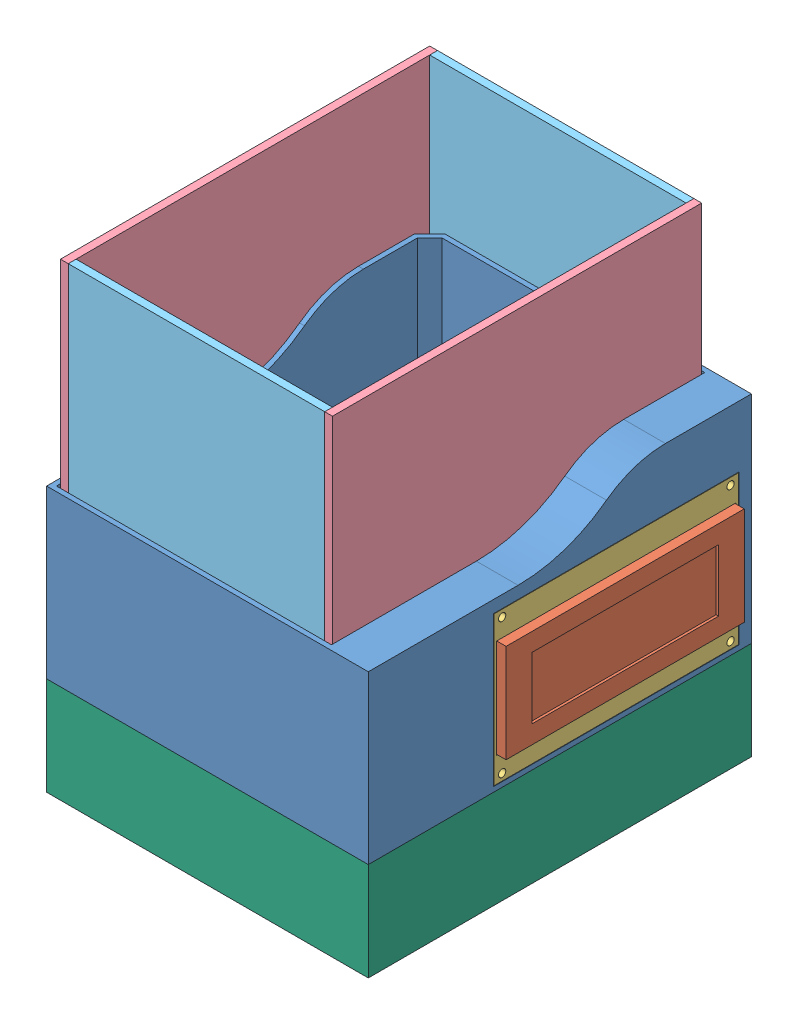
SolidWorks assembly MontagemGeral, configuration Valor predeterminado. Lengths in mm.
Overall size (134.6 188 156).
8 component instances, 6 part files, 22 mates.
Components (placement in the parent):
- Base-1: Base [Valor predeterminado] at origin size (131 88 156)
- 2004A-1: 2004A [Predeterminado] at (66.3 24.5 -23) x (0 0 -1) z (1 0 0) size (98 60 11.1)
- EspelhoFrontalLCD-1: EspelhoFrontalLCD [Valor predeterminado] at (68 0 0) x (0 0 -1) z (1 0 0) size (99.6 60.6 5)
- Acrilico Lateral-1: Acrilico Lateral [Valor predeterminado] at (55.5875 95 0) x (0 0 1) z (-1 0 0) size (150.35 90 3.17)
- Acrilico Lateral-2: Acrilico Lateral [Valor predeterminado] at (-52 95 0) x (0 0 1) z (-1 0 0) size (150.35 90 3.17)
- AcrilicoFrontal-1: AcrilicoFrontal [Valor predeterminado] at (0.2062 95 72) size (104.41 90 3.17)
- AcrilicoFrontal-2: AcrilicoFrontal [Valor predeterminado] at (0.2062 95 -75.175) size (104.41 90 3.17)
- CasePlacas-1: CasePlacas [Valor predeterminado] at (7.5 -48 0) size (131 40 156)
Mates (geometry in assembly coordinates):
- Coincidente1: coordinate: point of Base-1
- Simétrico1: symmetric aligned: plane of Base-1 through (53 55 -73) normal (0 0 1); plane of 2004A-1 through (53 55 27) normal (0 0 -1); plane of Base-1 through (66.3 24.5 -23) normal (0 0 -1)
- Simétrico2: symmetric aligned: plane of Base-1 through (53 -6 27) normal (0 1 0); plane of 2004A-1 through (53 55 27) normal (0 -1 0); plane of Base-1 through (66.3 24.5 -23) normal (0 1 0)
- Concêntrico1: concentric anti-aligned: cylinder of 2004A-1 through (65.5 -3 23.5) axis (1 0 0) radius 1.5; cylinder of EspelhoFrontalLCD-1 through (73 -3 23.5) axis (-1 0 0) radius 1.5
- Concêntrico2: concentric anti-aligned: cylinder of 2004A-1 through (65.5 52 -69.5) axis (1 0 0) radius 1.5; cylinder of EspelhoFrontalLCD-1 through (73 52 -69.5) axis (-1 0 0) radius 1.5
- Distância3: distance = 12.5 mm anti-aligned: plane of 2004A-1 through (65.5 24.5 -23) normal (-1 0 0); plane of Base-1 through (53 0 0) normal (1 0 0)
- Coincidente3: coincident aligned: plane of Base-1 through (73 40 -43) normal (1 0 0); plane of EspelhoFrontalLCD-1 through (73 0 0) normal (1 0 0)
- Largura1: width anti-aligned: plane of Base-1 through (56 50 -43) normal (-1 0 0); plane of Acrilico Lateral-1 through (52 50 -65.8284) normal (1 0 0); plane of Base-1 through (55.5875 95 0) normal (1 0 0); plane of Acrilico Lateral-1 through (52.4125 95 0) normal (-1 0 0)
- Largura2: width anti-aligned: plane of Base-1 through (56 50 -76) normal (0 0 1); plane of Acrilico Lateral-1 through (-56 50 76) normal (0 0 -1); plane of Base-1 through (52.4125 50 -75.175) normal (0 0 -1); plane of Acrilico Lateral-1 through (52.4125 50 75.175) normal (0 0 1)
- Coincidente4: coincident anti-aligned: plane of Base-1 through (0 50 0) normal (0 1 0); plane of Acrilico Lateral-1 through (52.4125 50 -75.175) normal (0 -1 0)
- Coincidente5: coincident aligned: plane of Acrilico Lateral-1 through (55.5875 95 0) normal (0 1 0); plane of Acrilico Lateral-2 through (-52 95 0) normal (0 1 0)
- Coincidente6: coincident aligned: plane of Acrilico Lateral-1 through (55.5875 95 0) normal (0 0 1); plane of Acrilico Lateral-2 through (-52 95 0) normal (0 0 1)
- Coincidente9: coincident anti-aligned: plane of Base-1 through (-52 50 65.8284) normal (-1 0 0); plane of Acrilico Lateral-2 through (-52 95 0) normal (1 0 0)
- Coincidente10: coincident anti-aligned: plane of Base-1 through (45.8284 50 72) normal (0 0 1); plane of AcrilicoFrontal-1 through (0.2062 95 72) normal (0 0 -1)
- Coincidente11: coincident anti-aligned: plane of Base-1 through (0 50 0) normal (0 1 0); plane of AcrilicoFrontal-1 through (-52 50 75.175) normal (0 -1 0)
- Coincidente12: coincident anti-aligned: plane of Acrilico Lateral-2 through (-52 95 0) normal (1 0 0); plane of AcrilicoFrontal-1 through (-52 50 75.175) normal (-1 0 0)
- Coincidente14: coincident anti-aligned: plane of Base-1 through (0 50 0) normal (0 1 0); plane of AcrilicoFrontal-2 through (-52 50 -72) normal (0 -1 0)
- Coincidente15: coincident anti-aligned: plane of Acrilico Lateral-2 through (-52 95 0) normal (1 0 0); plane of AcrilicoFrontal-2 through (-52 50 -72) normal (-1 0 0)
- Coincidente16: coincident anti-aligned: plane of Base-1 through (-45.8284 50 -72) normal (0 0 -1); plane of AcrilicoFrontal-2 through (0.2062 95 -72) normal (0 0 1)
- Coincidente17: coincident anti-aligned: plane of Base-1 through (0 -8 0) normal (0 -1 0); plane of CasePlacas-1 through (7.5 -8 0) normal (0 1 0)
- Coincidente18: coincident aligned: plane of Base-1 through (-58 80 78) normal (0 0 1); plane of CasePlacas-1 through (-58 -8 78) normal (0 0 1)
- Coincidente19: coincident aligned: plane of Base-1 through (-58 80 78) normal (-1 0 0); plane of CasePlacas-1 through (-58 -8 -78) normal (-1 0 0)
